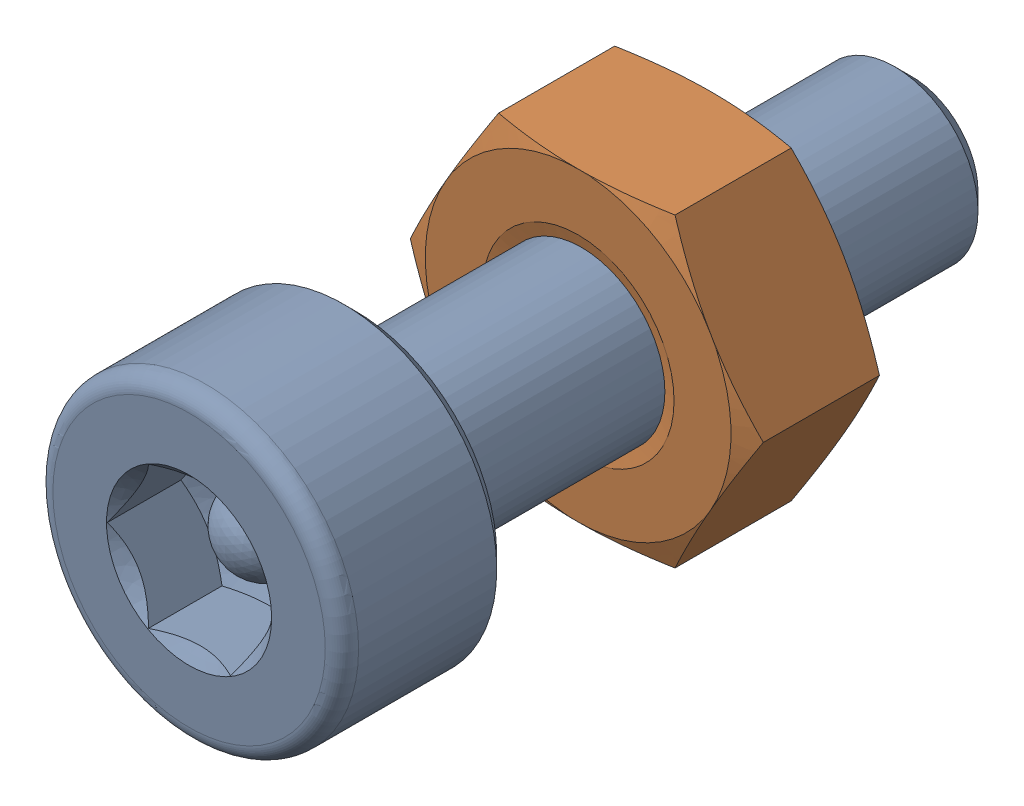
SolidWorks assembly Screw and Nut M3x010_013, configuration Varsayılan. Lengths in mm.
Overall size (6.35 5.5 13.14).
2 component instances, 2 part files, 0 mates.
Components (placement in the parent):
- M3x10-Screw012-1: M3x10-Screw012 [Varsayılan] at origin size (5.5 5.5 13.14)
- M3-Nut044-1: M3-Nut044 [Varsayılan] at (0 0 -4) x (-1 0 0) z (0 0 -1) size (6.35 5.5 2.4)
